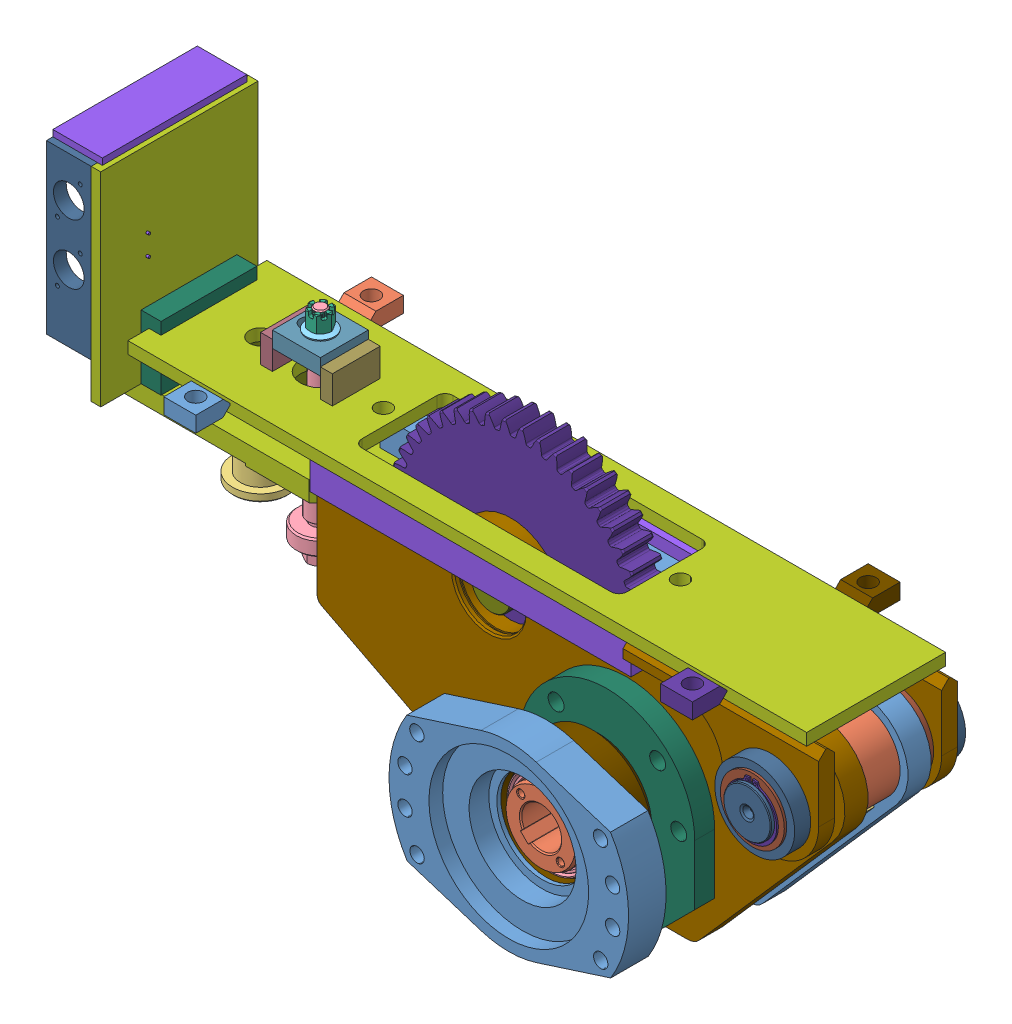
SolidWorks assembly g1_3_1_1, configuration 默认. Lengths in mm.
Overall size (943 530 331.8).
109 component instances, 72 part files, 46 mates.
Components (placement in the parent):
- g1_3_1_1_5_1-1: g1_3_1_1_5_1 [默认] at (310.2802 -95 30) x (-1 0 0) z (0 1 0) size (926 108 318.6)
  - g1_3_1_1_5-1_af1_1-1: g1_3_1_1_5-1_af1_1 [默认] at origin size (661 29 318.6)
  - g1_3_1_1_5-2_af0_1-1: g1_3_1_1_5-2_af0_1 [默认] at (-213.2 29 0) size (100 50 100)
  - g1_3_1_1_5-4_1-1: g1_3_1_1_5-4_1 [默认] at (-149.9151 54 -132.7301) x (0 1 0) z (-0.659692 0 0.751536) size (50 10 223)
  - g1_3_1_1_5-5_1-1: g1_3_1_1_5-5_1 [默认] at (20.5 54 -217) x (1 0 0) z (0 1 0) size (194 10 50)
  - g1_3_1_1_5-6_1-1: g1_3_1_1_5-6_1 [默认] at (248.4498 54 -161.5242) x (0 1 0) z (0.890083 0 0.455798) size (50 10 284)
  - g1_3_1_1_5-7_1-1: g1_3_1_1_5-7_1 [默认] at (377.8 54 -43.9) x (0 0 -1) z (0 1 0) size (87 10 50)
  - g1_3_1_1_5-9_af0_1-1: g1_3_1_1_5-9_af0_1 [默认] at (502.8 54 24.6) x (1 0 0) z (0 1 0) size (300 25 108)
  - g1_3_1_1_5-8_1-1: g1_3_1_1_5-8_1 [默认] at (437.8 54 49.6) x (1 0 0) z (0 1 0) size (60 50 60)
  - g1_3_1_1_5-1_af0_1-1: g1_3_1_1_5-1_af0_1 [默认] at (0 79 0) size (661 29 318.6)
- g1_3_1_1_4_1-1: g1_3_1_1_4_1 [默认] at (523.4802 -95 -33.3) x (1 0 0) z (0 -1 0) size (80 234 80)
  - g1_3_1_1_4-1_1-1: g1_3_1_1_4-1_1 [默认] at origin size (60 234 60.04)
  - g1_3_1_1_4-3_1-2: g1_3_1_1_4-3_1 [默认] at (0 224.3 0) size (80 3 80)
  - g1_3_1_1_4-2_1-1: g1_3_1_1_4-2_1 [默认] at (0 174.3 0) size (72 50 72)
  - g1_3_1_1_4-2_1-2: g1_3_1_1_4-2_1 [默认] at (0 9.7 0) size (72 50 72)
  - g1_3_1_1_4-2_1-3: g1_3_1_1_4-2_1 [默认] at (0 62.7 0) size (72 50 72)
  - g1_3_1_1_4-2_1-4: g1_3_1_1_4-2_1 [默认] at (0 121.3 0) size (72 50 72)
- g1_3_1_1_2_1-1: g1_3_1_1_2_1 [默认] at (310.2802 -195.4 0) x (0.999998 0.002137 0) z (0.002137 -0.999998 0) size (219.6 152 245)
  - g1_3_1_1_2-1_1-1: g1_3_1_1_2-1_1 [默认] at origin size (219.6 61 245)
  - g1_3_1_1_2-2_1-1: g1_3_1_1_2-2_1 [默认] at (0 152 0) x (-0.047609 0 0.998866) z (0 1 0) size (120.16 120.16 117)
  - g1_3_1_1_2-3_1-1: g1_3_1_1_2-3_1 [默认] at (-20.1525 129 20.1525) x (0 -1 0) z (0.707107 0 0.707107) size (28 11 14)
- g1_3_1_1_3_1-1: g1_3_1_1_3_1 [默认] at (137.4802 -78.4 83.75) x (0 0 -1) z (-0.004458 0.99999 0) size (103.5 321.87 322.01)
  - g1_3_1_1_3-1_1-1: g1_3_1_1_3-1_1 [默认] at origin size (103.5 52 52)
  - _X2_60F08F6E_X0_g1_3_1_1_3-2_1-1: _X2_60F08F6E_X0_g1_3_1_1_3-2_1 [默认] at (25 0 0) x (0 0 1) z (1 0 0) size (322.01 321.87 50.08)
- g1_3_1_1_1_2-1: g1_3_1_1_1_2 [默认] at (310.2802 -195.4 123.8) x (0.999998 0.002137 0) z (0.002137 -0.999998 0) size (300 165.8 228)
  - g1_3_1_1_1_1_1-1: g1_3_1_1_1_1_1 [默认] at origin size (300 112 228)
    - g1_3_1_1_1_1-2_af0_1-1: g1_3_1_1_1_1-2_af0_1 [默认] at (0 50 0) size (150 65 150)
    - g1_3_1_1_1_1-3_af0_1-1: g1_3_1_1_1_1-3_af0_1 [默认] at (0 140 0) size (300 47 228)
  - g1_3_1_1_1-2_1-1: g1_3_1_1_1-2_1 [默认] at (0 122.2 0) x (0.707107 0 0.707107) z (0.707107 0 -0.707107) size (90 126 90)
  - g1_3_1_1_1-1_1-1: g1_3_1_1_1-1_1 [默认] at (0 77 0) x (0 1 0) z (0 0 1) size (20 110 110)
  - b90x110x12_gb9877_1_1-1: b90x110x12_gb9877_1_1 [默认] at (0 66.9 0) size (108.6 17.9 108.6)
    - b90x110x12_gb9877_1_rubber_1-1: b90x110x12_gb9877_1_rubber_1 [默认] at origin size (108.6 12 108.6)
    - b90x110x12_gb9877_1_frame_1-1: b90x110x12_gb9877_1_frame_1 [默认] at (0 -2.4 0) x (-1 0 0) z (0 0 1) size (107.2 9.5 107.2)
  - b90x110x12_gb9877_1_1-2: b90x110x12_gb9877_1_1 [默认] at (0 104.8 0) size (108.6 17.9 108.6)
    - b90x110x12_gb9877_1_rubber_1-1: b90x110x12_gb9877_1_rubber_1 [默认] at origin size (108.6 12 108.6)
    - b90x110x12_gb9877_1_frame_1-1: b90x110x12_gb9877_1_frame_1 [默认] at (0 -2.4 0) x (-1 0 0) z (0 0 1) size (107.2 9.5 107.2)
  - 80_gb894_1_1-1: 80_gb894_1_1 [默认] at (-2.4 11.1 -38.1746) x (1 0 0) z (0 -1 0) size (85.83 90.87 2.5)
- g1_3_1_1_6_1-1: g1_3_1_1_6_1 [默认] at (137.4802 0 84) x (-1 0 0) z (0 0 1) size (875 200 260)
  - g1_3_1_1_6-4_af0_1-1: g1_3_1_1_6-4_af0_1 [默认] at origin size (850 15 174)
  - g1_3_1_1_6-8_1-1: g1_3_1_1_6-8_1 [默认] at (0 40 57) x (1 0 0) z (0 -1 0) size (402 20 44.8)
  - g1_3_1_1_6-8_1-2: g1_3_1_1_6-8_1 [默认] at (0 40 -77) x (1 0 0) z (0 -1 0) size (402 20 44.8)
  - g1_3_1_1_6-1_1-1: g1_3_1_1_6-1_1 [默认] at (-386 95 -87) x (1 0 0) z (0 -1 0) size (245 20 140)
  - g1_3_1_1_6-1_1-2: g1_3_1_1_6-1_1 [默认] at (-386 95 67) x (1 0 0) z (0 -1 0) size (245 20 140)
  - g1_3_1_1_6-3_1-1: g1_3_1_1_6-3_1 [默认] at (-386 95 87) x (-1 0 0) z (0 1 0) size (100 20 100)
  - g1_3_1_1_6-3_1-2: g1_3_1_1_6-3_1 [默认] at (-386 95 -107) x (-1 0 0) z (0 1 0) size (100 20 100)
  - g1_3_1_1_6-2_1-1: g1_3_1_1_6-2_1 [默认] at (-386 95 57) x (-1 0 0) z (0 1 0) size (100 10 100)
  - g1_3_1_1_6-2_1-2: g1_3_1_1_6-2_1 [默认] at (-386 95 -57) x (1 0 0) z (0 1 0) size (100 10 100)
  - g1_3_1_1_6-9_1-1: g1_3_1_1_6-9_1 [默认] at (220 -17 0) x (0 1 0) z (0 0 -1) size (35 15 60)
  - g1_3_1_1_6-9_af0_1-1: g1_3_1_1_6-9_af0_1 [默认] at (310 -17 0) x (0 1 0) z (0 0 1) size (35 15 60)
  - g1_3_1_1_6-10_1-1: g1_3_1_1_6-10_1 [默认] at (265 -45 0) size (60 20 60)
  - g1_3_1_1_6-12_af0_1-1: g1_3_1_1_6-12_af0_1 [默认] at (434 25 0.5) x (0 0 1) z (0 -1 0) size (120 25 80)
  - g1_3_1_1_6-11_af0_1-1: g1_3_1_1_6-11_af0_1 [默认] at (357 15 0) size (94 40 60)
  - g1_3_1_1_6-5_af0_1-1: g1_3_1_1_6-5_af0_1 [默认] at (-311 -5 108.5) x (0 0 -1) z (1 0 0) size (43 19.6 40)
  - g1_3_1_1_6-5_af1_1-1: g1_3_1_1_6-5_af1_1 [默认] at (-311 -5 -108.5) x (0 0 1) z (-1 0 0) size (43 19.6 40)
  - g1_3_1_1_6-5_af2_1-1: g1_3_1_1_6-5_af2_1 [默认] at (311 -5 108.5) x (0 0 -1) z (1 0 0) size (43 19.6 40)
  - g1_3_1_1_6-5_af3_1-1: g1_3_1_1_6-5_af3_1 [默认] at (311 -5 -108.5) x (0 0 1) z (-1 0 0) size (43 19.6 40)
- g1_3_1_1-1_1-1: g1_3_1_1-1_1 [默认] at (-202.5198 -45.5 84) x (1 0 -0.00083) z (-0.00083 0 -1) size (70 135 70)
- g1_3_1_1_7_1-1: g1_3_1_1_7_1 [默认] at (-127.5198 -16.0167 84) x (0 1 0) z (0.020278 0 0.999794) size (272.02 60 60)
  - g1_3_1_1_7-1_1-1: g1_3_1_1_7-1_1 [默认] at origin size (272.02 60 60)
  - a35_5_gb1972_1-1: a35_5_gb1972_1 [默认] at (39.2167 0 0) x (0 0.075145 0.997173) z (0 0.997173 -0.075145) size (35.5 7.2 35.5)
  - a35_5_gb1972_1-2: a35_5_gb1972_1 [默认] at (62.8167 0 0) x (0 -0.99777 0.066751) z (0 -0.066751 -0.99777) size (35.5 7.2 35.5)
  - m16a_gb6178_1-1: m16a_gb6178_1 [默认] at (85.8167 13.8564 0) x (0 -1 0) z (-1 0 0) size (27.71 24 20.8)
- g1_3_1_1_8_1-1: g1_3_1_1_8_1 [默认] at (-291.5198 62.5 96.5) x (0 0 -1) z (0 1 0) size (197 71 268.3)
  - g1_3_1_1_8_1_af0_1-1: g1_3_1_1_8_1_af0_1 [默认] at origin size (197 68 263)
    - g1_3_1_1_8_1-3_af1_1-1: g1_3_1_1_8_1-3_af1_1 [默认] at origin size (197 12 255)
    - g1_3_1_1_8_1-1_1-1: g1_3_1_1_8_1-1_1 [默认] at (0 37 127.5) x (1 0 0) z (0 -1 0) size (181 8 62)
    - g1_3_1_1_8_1-2_af1_1-1: g1_3_1_1_8_1-2_af1_1 [默认] at (98.5 40 22.5) x (0 1 0) z (0 0 1) size (56 16 210)
    - g1_3_1_1_8_1-2_af0_1-1: g1_3_1_1_8_1-2_af0_1 [默认] at (-98.5 40 22.5) x (0 1 0) z (0 0 -1) size (56 16 210)
    - g1_3_1_1_8_1-5_1-1: g1_3_1_1_8_1-5_1 [默认] at (0 40 -82.5) x (1 0 0) z (0 1 0) size (165 8 56)
    - g1_3_1_1_8_1-6_1-1: g1_3_1_1_8_1-6_1 [默认] at (27.5 40 -106) x (0 1 0) z (0 0 -1) size (56 6 31)
    - g1_3_1_1_8_1-6_1-2: g1_3_1_1_8_1-6_1 [默认] at (-8.5 40 -106) x (0 1 0) z (0 0 -1) size (56 6 31)
    - g1_3_1_1_8_1-4_af1_1-1: g1_3_1_1_8_1-4_af1_1 [默认] at (-10 12 5) size (105 17 85)
    - g1_3_1_1_8_1-8_af0_1-1: g1_3_1_1_8_1-8_af0_1 [默认] at (12.5 40 -127.5) x (0 1 0) z (1 0 0) size (56 6 54)
  - g1_3_1_1_8-3_1-1: g1_3_1_1_8-3_1 [默认] at (12.5 37 -32.7987) x (0 0 -1) z (0 1 0) size (229 15 15)
  - g1_3_1_1_8-6_1-1: g1_3_1_1_8-6_1 [默认] at (12.5 37 30.1) x (-1 0 0) z (0 1 0) size (26 60 26)
  - g1_3_1_1_8-5_1-1: g1_3_1_1_8-5_1 [默认] at (12.5 29 -27.5) size (60 24 20)
  - g1_3_1_1_8-9_af0_1-1: g1_3_1_1_8-9_af0_1 [默认] at (-42.5 17 5.5) size (34 10 74)
  - g1_3_1_1_8-10_1-1: g1_3_1_1_8-10_1 [默认] at (12.5 37 -127.5) x (1 0 0) z (0 1 0) size (40 2 32)
  - ya2x20x90-2_gb2089_af0_1-1: ya2x20x90-2_gb2089_af0_1 [默认] at (12.5 37 -82.5) x (0 0 -1) z (1 0 0) size (92.3 24.62 24.71)
  - 14x2_65_gb3452_1_1-1: 14x2_65_gb3452_1_1 [默认] at (12.5 37 -124.5) x (0 0 1) z (0 1 0) size (2.65 19.37 19.38)
  - 15_gb894_1_1-1: 15_gb894_1_1 [默认] at (12 29.8675 -73.9) size (17.18 18.67 1.11)
  - 15_gb894_1_1-2: 15_gb894_1_1 [默认] at (12 29.8675 29) size (17.18 18.67 1.11)
  - 8_gb93_1-1: 8_gb93_1 [默认] at (32.5 53 -27.5) x (-1 0 0) z (0 1 0) size (12.3 12.3 2.1)
  - m8x40_gb5782_1-1: m8x40_gb5782_1 [默认] at (32.5 55.1 -27.5) size (15.01 45.3 13)
  - 8_gb93_1-2: 8_gb93_1 [默认] at (-7.5 53 -27.5) x (-1 0 0) z (0 1 0) size (12.3 12.3 2.1)
  - m8x40_gb5782_1-2: m8x40_gb5782_1 [默认] at (-7.5 55.1 -27.5) size (15.01 45.3 13)
  - m3x10_gb818_1-1: m3x10_gb818_1 [默认] at (57.5 2 60.5) size (5.81 12.5 5.77)
  - m3x10_gb818_1-2: m3x10_gb818_1 [默认] at (57.5 2 100.5) size (5.81 12.5 5.77)
  - m3x10_gb818_1-3: m3x10_gb818_1 [默认] at (-17.5 2 100.5) size (5.81 12.5 5.77)
  - m3x10_gb818_1-4: m3x10_gb818_1 [默认] at (-57.5 2 100.5) size (5.81 12.5 5.77)
  - m3x30_gb818_1-1: m3x30_gb818_1 [默认] at (-40.5 -3 7.5) size (5.81 32.5 5.77)
  - m3x30_gb818_1-2: m3x30_gb818_1 [默认] at (-40.5 -3 32.9) size (5.81 32.5 5.77)
  - 6_gb93_1-9: 6_gb93_1 [默认] at (-52.5 28.6 -17.5) x (1 0 0) z (0 -1 0) size (9.3 9.3 1.6)
  - m6x20_gb5783_1-9: m6x20_gb5783_1 [默认] at (-52.5 28.6 -17.5) size (11.55 24 10)
  - 6_gb93_1-10: 6_gb93_1 [默认] at (-32.5 28.6 -17.5) x (1 0 0) z (0 -1 0) size (9.3 9.3 1.6)
  - m6x20_gb5783_1-10: m6x20_gb5783_1 [默认] at (-32.5 28.6 -17.5) size (11.55 24 10)
  - 5x14_gb119_2_1-1: 5x14_gb119_2_1 [默认] at (-42.5 27 -3.5) size (5 14 5)
  - m3x6_gb818_1-1: m3x6_gb818_1 [默认] at (27.5 37 -123.5) x (1 0 0) z (0 1 0) size (5.81 8.5 5.77)
  - m3x6_gb818_1-2: m3x6_gb818_1 [默认] at (-2.5 37 -123.5) x (1 0 0) z (0 1 0) size (5.81 8.5 5.77)
- _X2_57AB5708_X0_16_gb93_1-9: _X2_57AB5708_X0_16_gb93_1 [默认] at (-303.5198 -50 44) x (0 0.924225 0.381849) z (-1 0 0) size (24.4 24.4 4.1)
- _X2_87BA6813_X0_m16x35_gb5783_10_1-1: _X2_87BA6813_X0_m16x35_gb5783_10_1 [默认] at (-307.6198 -50 44) x (0 -0.866025 -0.5) z (0 0.5 -0.866025) size (27.71 45 24)
- _X2_57AB5708_X0_16_gb93_1-10: _X2_57AB5708_X0_16_gb93_1 [默认] at (-303.5198 -50 124) x (0 0.924225 0.381849) z (-1 0 0) size (24.4 24.4 4.1)
- _X2_87BA6813_X0_m16x35_gb5783_10_1-2: _X2_87BA6813_X0_m16x35_gb5783_10_1 [默认] at (-307.6198 -50 124) x (0 -0.866025 -0.5) z (0 0.5 -0.866025) size (27.71 45 24)
- g1_3_1_1_1_1-1_af0_1-1: g1_3_1_1_1_1-1_af0_1 [默认] at (310.2802 -195.4 113) x (1 0 0) z (0 -1 0) size (220 42 245)
- g1_3_1_1_7-2_1-1: g1_3_1_1_7-2_1 [默认] at (-159.2741 -95.4 83.9778) x (1 0 0.0007) z (0 -1 0) size (63.51 55 25)
- g1_3_1_1_4-3_1-2: g1_3_1_1_4-3_1 [默认] at (523.4802 -95 -23.6) x (-0.923728 -0.383049 0) z (0.383049 -0.923728 0) size (80 3 80)
- 60_gb894_1_1-2: 60_gb894_1_1 [默认] at (525.4302 -66.5668 -28.6) x (-1 0 0) z (0 0 1) size (65.16 69.76 2)
- 60_gb894_1_1-3: 60_gb894_1_1 [默认] at (525.4302 -66.5668 194) x (-1 0 0) z (0 0 1) size (65.16 69.76 2)
- 16x10x45_gb1096_1-2: 16x10x45_gb1096_1 [默认] at (137.3687 -53.4002 83.25) x (0 0 -1) z (0.004458 -0.99999 0) size (45 16 10)
Mates (geometry in assembly coordinates):
- 重合1: coincident anti-aligned: plane of g1_3_1_1_2_1-1/g1_3_1_1_2-3_1-1 through (285.2105 -210.6564 129) normal (-0.708616 0.705594 0); plane of g1_3_1_1_1_2-1/g1_3_1_1_1-2_1-1 through (284.9988 -210.869 246) normal (0.708616 -0.705594 0)
- 重合2: coincident anti-aligned: plane of g1_3_1_1_2_1-1/g1_3_1_1_2-2_1-1 through (310.2802 -195.4 120) normal (0 0 1); plane of g1_3_1_1_1_2-1/g1_3_1_1_1-2_1-1 through (310.2802 -195.4 120) normal (0 0 -1)
- 同心3: concentric aligned: cylinder of g1_3_1_1_2_1-1/g1_3_1_1_2-2_1-1 through (310.2802 -195.4 29.15) axis (0 0 1) radius 25; cylinder of g1_3_1_1_1_2-1/g1_3_1_1_1-2_1-1 through (310.2802 -195.4 246) axis (0 0 1) radius 25
- 同心9: concentric anti-aligned: cylinder of g1_3_1_1_8_1-1/g1_3_1_1_8_1_af0_1-1/g1_3_1_1_8_1-3_af1_1-1 through (-303.5198 -50 124) axis (1 0 0) radius 8.5; cylinder of _X2_87BA6813_X0_m16x35_gb5783_10_1-2 through (-270.8698 -50 124) axis (-1 0 0) radius 8
- 同心12: concentric anti-aligned: cylinder of g1_3_1_1_6_1-1/g1_3_1_1_6-12_af0_1-1 through (-248.0035 -50 44) axis (1 0 0) radius 7; cylinder of _X2_87BA6813_X0_m16x35_gb5783_10_1-1 through (-270.8698 -50 44) axis (-1 0 0) radius 8
- 同心13: concentric aligned: cylinder of _X2_57AB5708_X0_16_gb93_1-10 through (-303.5198 -50 124) axis (-1 0 0) radius 8.1; cylinder of _X2_87BA6813_X0_m16x35_gb5783_10_1-2 through (-270.8698 -50 124) axis (-1 0 0) radius 8
- 同心14: concentric aligned: cylinder of _X2_57AB5708_X0_16_gb93_1-9 through (-303.5198 -50 44) axis (-1 0 0) radius 8.1; cylinder of _X2_87BA6813_X0_m16x35_gb5783_10_1-1 through (-270.8698 -50 44) axis (-1 0 0) radius 8
- 重合3: coincident anti-aligned: plane of _X2_57AB5708_X0_16_gb93_1-9 through (-307.6198 -50 44) normal (-1 0 0); plane of _X2_87BA6813_X0_m16x35_gb5783_10_1-1 through (-307.6198 -50 44) normal (1 0 0)
- 重合4: coincident anti-aligned: plane of _X2_57AB5708_X0_16_gb93_1-10 through (-307.6198 -50 124) normal (-1 0 0); plane of _X2_87BA6813_X0_m16x35_gb5783_10_1-2 through (-307.6198 -50 124) normal (1 0 0)
- 同心15: concentric aligned: cylinder of g1_3_1_1_8_1-1/g1_3_1_1_8_1_af0_1-1/g1_3_1_1_8_1-3_af1_1-1 through (-303.5198 -50 44) axis (-1 0 0) radius 8.5; cylinder of _X2_87BA6813_X0_m16x35_gb5783_10_1-1 through (-270.8698 -50 44) axis (-1 0 0) radius 8
- 同心18: concentric aligned: cylinder of g1_3_1_1_6_1-1/g1_3_1_1_6-11_af0_1-1 through (-202.5198 71.0063 84) axis (0 -1 0) radius 14; cylinder of g1_3_1_1-1_1-1 through (-202.5198 -19.25 84) axis (0 -1 0) radius 15
- 同心20: concentric anti-aligned: cylinder of g1_3_1_1_5_1-1/g1_3_1_1_5-9_af0_1-1 through (-202.5198 -95.4 84) axis (0 1 0) radius 27; cylinder of g1_3_1_1-1_1-1 through (-202.5198 -50.5 84) axis (0 -1 0) radius 25
- 重合10: coincident anti-aligned: plane of g1_3_1_1_8_1-1/g1_3_1_1_8_1_af0_1-1/g1_3_1_1_8_1-3_af1_1-1 through (-303.5198 62.5 96.5) normal (-1 0 0); plane of _X2_57AB5708_X0_16_gb93_1-9 through (-303.5198 -50 44) normal (1 0 0)
- 重合12: coincident anti-aligned: plane of g1_3_1_1_8_1-1/g1_3_1_1_8_1_af0_1-1/g1_3_1_1_8_1-3_af1_1-1 through (-303.5198 62.5 96.5) normal (-1 0 0); plane of _X2_57AB5708_X0_16_gb93_1-10 through (-303.5198 -50 124) normal (1 0 0)
- 重合13: coincident anti-aligned: plane of g1_3_1_1_6_1-1/g1_3_1_1_6-12_af0_1-1 through (-291.5198 0 84) normal (-1 0 0); plane of g1_3_1_1_8_1-1/g1_3_1_1_8_1_af0_1-1/g1_3_1_1_8_1-3_af1_1-1 through (-291.5198 62.5 96.5) normal (1 0 0)
- 同心23: concentric aligned: cylinder of g1_3_1_1_5_1-1/g1_3_1_1_5-1_af1_1-1 through (523.4802 -95 30) axis (0 0 1) radius 36; cylinder of g1_3_1_1_6_1-1/g1_3_1_1_6-3_1-2 through (523.4802 -95 -23) axis (0 0 1) radius 36
- 同心24: concentric aligned: cylinder of g1_3_1_1_4_1-1/g1_3_1_1_4-2_1-2 through (523.4802 -95 -23.6) axis (0 0 1) radius 36; cylinder of g1_3_1_1_6_1-1/g1_3_1_1_6-3_1-2 through (523.4802 -95 -23) axis (0 0 1) radius 36
- 重合14: coincident anti-aligned: plane of g1_3_1_1_4_1-1/g1_3_1_1_4-3_1-2 through (523.4802 -95 191) normal (0 0 -1); plane of g1_3_1_1_6_1-1/g1_3_1_1_6-3_1-1 through (523.4802 -95 191) normal (0 0 1)
- 同心25: concentric aligned: cylinder of g1_3_1_1_5_1-1/g1_3_1_1_5-1_af1_1-1 through (137.4802 -78.4 30) axis (0 0 1) radius 45; cylinder of g1_3_1_1_3_1-1/g1_3_1_1_3-1_1-1 through (137.4802 -78.4 26.825) axis (0 0 1) radius 25
- 同心26: concentric aligned: cylinder of g1_3_1_1_5_1-1/g1_3_1_1_5-1_af1_1-1 through (310.2802 -195.4 30) axis (0 0 1) radius 75; cylinder of g1_3_1_1_2_1-1/g1_3_1_1_2-1_1-1 through (310.2802 -195.4 30) axis (0 0 1) radius 75
- 重合16: coincident anti-aligned: plane of g1_3_1_1_5_1-1/g1_3_1_1_5-1_af1_1-1 through (310.2802 -95 30) normal (0 0 -1); plane of g1_3_1_1_2_1-1/g1_3_1_1_2-1_1-1 through (310.2802 -195.4 30) normal (0 0 1)
- 重合17: coincident anti-aligned: plane of g1_3_1_1_5_1-1/g1_3_1_1_5-1_af1_1-1; plane of ? through (523.5275 -270.9624 278.2595) normal (0 -1 0)
- 重合19: coincident aligned: plane of g1_3_1_1_5_1-1/g1_3_1_1_5-1_af0_1-1 through (137.4802 -78.4 128.8) normal (0 0 1); plane of g1_3_1_1_3_1-1/g1_3_1_1_3-1_1-1 through (137.4802 -78.4 128.8) normal (0 0 1)
- 重合28: coincident anti-aligned: plane of g1_3_1_1_2_1-1/g1_3_1_1_2-1_1-1 through (310.2802 -195.4 0) normal (0 0 -1); plane of assembly through (0 0 0) normal (0 0 1)
- 重合31: coincident aligned: plane of g1_3_1_1_6_1-1/g1_3_1_1_6-4_af0_1-1 through (137.4802 0 84) normal (0 1 0); plane of assembly through (0 0 0) normal (0 1 0)
- 同心28: concentric aligned: cylinder of g1_3_1_1_6_1-1/g1_3_1_1_6-12_af0_1-1 through (-248.0035 -50 124) axis (-1 0 0) radius 7; cylinder of _X2_87BA6813_X0_m16x35_gb5783_10_1-2 through (-270.8698 -50 124) axis (-1 0 0) radius 8
- 同心29: concentric aligned: cylinder of g1_3_1_1_5_1-1/g1_3_1_1_5-1_af0_1-1 through (310.2802 -195.4 109) axis (0 0 1) radius 75; cylinder of g1_3_1_1_1_1-1_af0_1-1 through (310.2802 -195.4 -384.4109) axis (0 0 1) radius 75
- 同心30: concentric aligned: cylinder of g1_3_1_1_5_1-1/g1_3_1_1_5-1_af0_1-1 through (246.6802 -131.8 108.5324) axis (0 0 1) radius 5.1; cylinder of g1_3_1_1_1_1-1_af0_1-1 through (246.6802 -131.8 163) axis (0 0 1) radius 10
- 重合33: coincident anti-aligned: plane of g1_3_1_1_5_1-1/g1_3_1_1_5-1_af0_1-1 through (310.2802 -95 138) normal (0 0 1); plane of g1_3_1_1_1_1-1_af0_1-1 through (310.2802 -195.4 138) normal (0 0 -1)
- 平行2: parallel aligned: plane of ? through (593.4401 -66.5668 194.2) normal (1 0 0); plane of g1_3_1_1_6_1-1/g1_3_1_1_6-1_1-2 through (655.3901 -95 151) normal (1 0 0)
- 重合37: coincident anti-aligned: plane of g1_3_1_1_6_1-1/g1_3_1_1_6-11_af0_1-1 through (-172.5198 -50.5 114) normal (0 -1 0); plane of g1_3_1_1-1_1-1 through (-202.5198 -50.5 84) normal (0 1 0)
- 平行5: parallel anti-aligned: plane of g1_3_1_1_8_1-1/g1_3_1_1_8_1_af0_1-1/g1_3_1_1_8_1-5_1-1 through (-331.5198 -28 96.5) normal (0 -1 0); plane of _X2_87BA6813_X0_m16x35_gb5783_10_1-2 through (-307.6198 -38 130.9282) normal (0 1 0)
- 平行6: parallel anti-aligned: plane of g1_3_1_1_8_1-1/g1_3_1_1_8_1_af0_1-1/g1_3_1_1_8_1-5_1-1 through (-331.5198 -28 96.5) normal (0 -1 0); plane of _X2_87BA6813_X0_m16x35_gb5783_10_1-1 through (-307.6198 -38 50.9282) normal (0 1 0)
- 同心33: concentric anti-aligned: cylinder of g1_3_1_1_6_1-1/g1_3_1_1_6-10_1-1 through (-127.5198 45 84) axis (0 -1 0) radius 10; cylinder of g1_3_1_1_7_1-1/g1_3_1_1_7-1_1-1 through (-127.5198 -471.3188 84) axis (0 1 0) radius 8.9
- 同心34: concentric anti-aligned: cylinder of g1_3_1_1_7_1-1/g1_3_1_1_7-1_1-1 through (-127.5198 -471.3188 84) axis (0 1 0) radius 16; cylinder of g1_3_1_1_7-2_1-1 through (-127.5198 -95.4 84) axis (0 -1 0) radius 16.376
- 重合38: coincident anti-aligned: plane of g1_3_1_1_5_1-1/g1_3_1_1_5-8_1-1 through (-127.5198 -95.4 84) normal (0 -1 0); plane of g1_3_1_1_7-2_1-1 through (-159.2741 -95.4 83.9778) normal (0 1 0)
- 距离1: distance = 4 mm anti-aligned: plane of g1_3_1_1_7_1-1/g1_3_1_1_7-1_1-1 through (-127.5198 21 84) normal (0 1 0); plane of g1_3_1_1_6_1-1/g1_3_1_1_6-10_1-1 through (-127.5198 25 84) normal (0 -1 0)
- 重合40: coincident anti-aligned: plane of g1_3_1_1_4_1-1/g1_3_1_1_4-2_1-2 through (523.4802 -95 -23.6) normal (0 0 -1); plane of g1_3_1_1_4-3_1-2 through (523.4802 -95 -23.6) normal (0 0 1)
- 同心35: concentric anti-aligned: cylinder of g1_3_1_1_4_1-1/g1_3_1_1_4-1_1-1 through (523.4802 -95 -33.3) axis (0 0 1) radius 30; cylinder of g1_3_1_1_4-3_1-2 through (523.4802 -95 -23.6) axis (0 0 -1) radius 30.5
- 同心36: concentric aligned: cylinder of g1_3_1_1_4_1-1/g1_3_1_1_4-1_1-1 through (523.4802 -95 450.0941) axis (0 0 1) radius 28.5; cylinder of 60_gb894_1_1-2 through (523.4802 -95 -28.6) axis (0 0 1) radius 28.5
- 重合41: coincident anti-aligned: plane of g1_3_1_1_4-3_1-2 through (523.4802 -95 -26.6) normal (0 0 -1); plane of 60_gb894_1_1-2 through (525.4302 -66.5668 -26.6) normal (0 0 1)
- 重合42: coincident anti-aligned: plane of g1_3_1_1_4_1-1/g1_3_1_1_4-3_1-2 through (523.4802 -95 194) normal (0 0 1); plane of 60_gb894_1_1-3 through (525.4302 -66.5668 194) normal (0 0 -1)
- 同心37: concentric aligned: cylinder of g1_3_1_1_4_1-1/g1_3_1_1_4-1_1-1 through (523.4802 -95 -282.6941) axis (0 0 1) radius 28.5; cylinder of 60_gb894_1_1-3 through (523.4802 -95 194) axis (0 0 1) radius 28.5
- 重合51: coincident anti-aligned: plane of g1_3_1_1_3_1-1/g1_3_1_1_3-1_1-1 through (137.391 -58.4002 83.75) normal (-0.004458 0.99999 0); plane of 16x10x45_gb1096_1-2 through (137.391 -58.4002 83.25) normal (0.004458 -0.99999 0)
- 同心39: concentric aligned: cylinder of g1_3_1_1_3_1-1/g1_3_1_1_3-1_1-1 through (137.3643 -52.4003 68.75) axis (-0.004458 0.99999 0) radius 8; cylinder of 16x10x45_gb1096_1-2 through (137.3911 -58.4158 68.75) axis (-0.004458 0.99999 0) radius 8
- 重合52: coincident anti-aligned: plane of g1_3_1_1_3_1-1/g1_3_1_1_3-1_1-1 through (145.3642 -52.3646 98.75) normal (-0.99999 -0.004458 0); plane of 16x10x45_gb1096_1-2 through (145.3464 -48.3646 60.75) normal (0.99999 0.004458 0)
